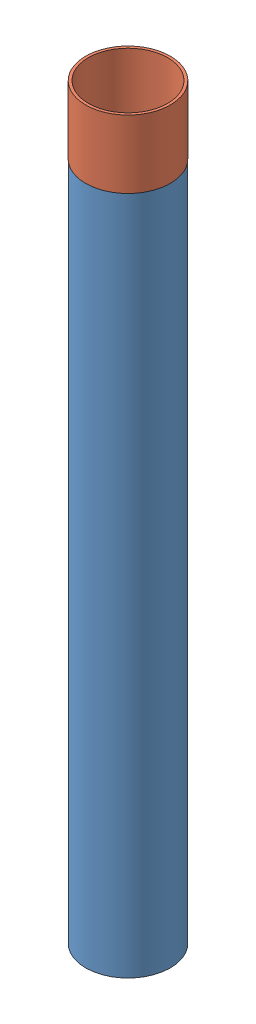
SolidWorks assembly S2_B_Airframe, configuration Default. Lengths in mm.
Overall size (94.9 838.2 94.9).
2 component instances, 2 part files, 6 mates.
Components (placement in the parent):
- S2_B_Aft_Airframe-1: S2_B_Aft_Airframe [Default] at origin size (94.9 762 94.9)
- S2_B_Forward_Airframe-1: S2_B_Forward_Airframe [Default] at (0 762 0) size (94.9 76.2 94.9)
Mates (geometry in assembly coordinates):
- Parallel1: parallel aligned: plane of S2_B_Aft_Airframe-1 through (0 0 0) normal (0 0 1)
- Coincident1: coincident aligned: line of S2_B_Aft_Airframe-1 through (838.2 0 -38.1) axis (0 0 1)
- Coincident2: coincident aligned: plane of S2_B_Aft_Airframe-1 through (0 0 0) normal (0 1 0)
- Parallel2: parallel aligned: plane of S2_B_Forward_Airframe-1 through (0 762 0) normal (0 0 1)
- Coincident3: coincident aligned: plane of S2_B_Aft_Airframe-1 through (0 762 0) normal (0 1 0); plane of S2_B_Forward_Airframe-1 through (0 762 0) normal (0 1 0)
- Coincident4: coincident aligned: line of S2_B_Forward_Airframe-1 through (83.82 0 758.19) axis (0 0 1)
